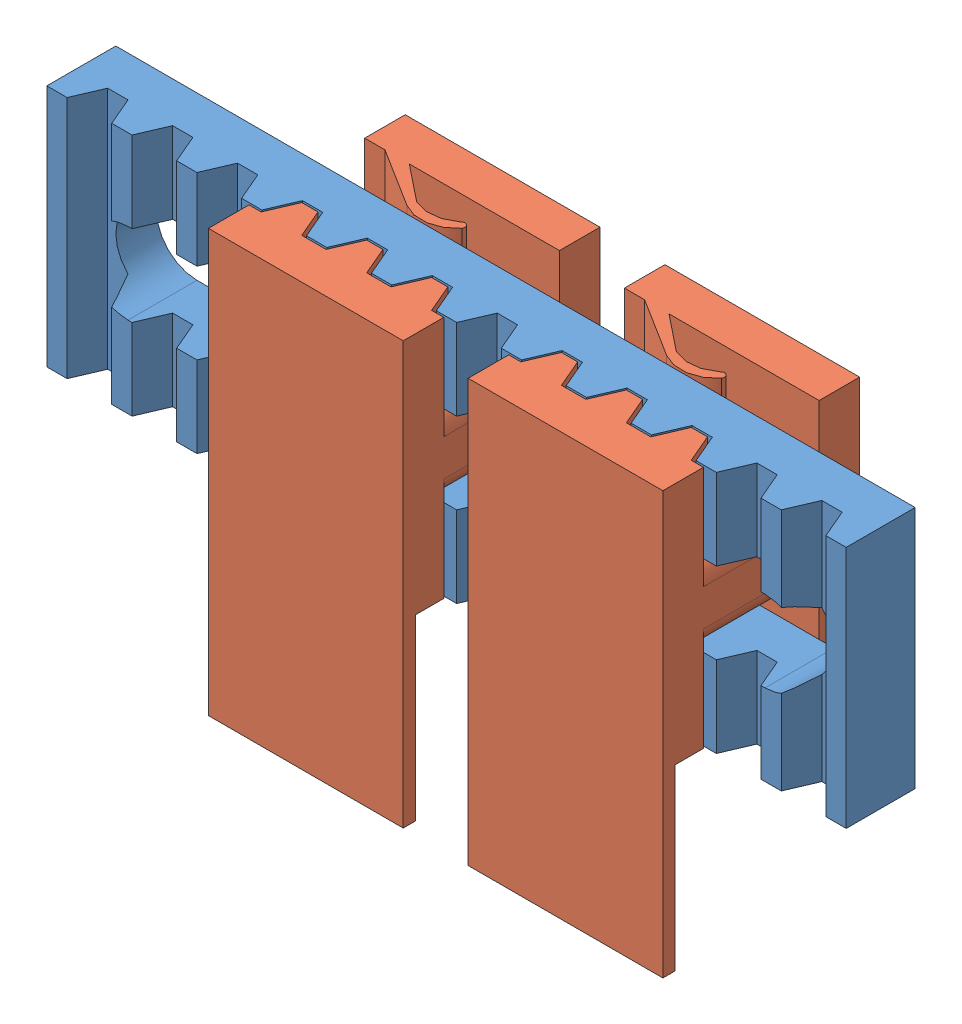
SolidWorks assembly locking mechanism, configuration Default. Lengths in mm.
Overall size (197 104 48.5).
3 component instances, 2 part files, 8 mates.
Components (placement in the parent):
- lock-1: lock [Default] at (99.9471 75.9801 126.6201) size (197 60 17)
- thigh-2: thigh [Default] at (73.7886 135.9801 154.1201) x (-1 0 0) z (0 0 1) size (48 104 48.5)
- thigh-3: thigh [Default] at (137.7886 135.9801 154.1201) x (-1 0 0) z (0 0 1) size (48 104 48.5)
Mates (geometry in assembly coordinates):
- Coincident1: coincident aligned: plane of lock-1 through (99.9471 135.9801 126.6201) normal (0 1 0); plane of thigh-2 through (73.7886 135.9801 154.1201) normal (0 1 0)
- Parallel1: parallel aligned: plane of lock-1 through (99.9471 135.9801 126.6201) normal (0 0 -1); plane of thigh-2 through (73.7886 135.9801 105.6201) normal (0 0 -1)
- Coincident4: coincident aligned: plane of lock-1 through (99.9471 135.9801 126.6201) normal (0 1 0); plane of thigh-3 through (137.7886 135.9801 154.1201) normal (0 1 0)
- Parallel2: parallel aligned: plane of lock-1 through (99.9471 135.9801 126.6201) normal (0 0 -1); plane of thigh-3 through (137.7886 135.9801 105.6201) normal (0 0 -1)
- Distance9: distance = 0.5 mm anti-aligned: plane of thigh-2 through (93.7768 75.9801 137.1201) normal (0 0 -1); plane of lock-1 through (99.9471 135.9801 136.6201) normal (0 0 1)
- Distance10: distance = 0.5 mm anti-aligned: plane of lock-1 through (99.9471 135.9801 136.6201) normal (0 0 1); plane of thigh-3 through (141.7768 75.9801 137.1201) normal (0 0 -1)
- Distance11: distance = 0.5 mm anti-aligned: plane of thigh-2 through (57.7768 75.9801 137.1201) normal (-0.919145 0 -0.393919); plane of lock-1 through (67.6626 135.9801 112.7839) normal (0.919145 0 0.393919)
- Distance12: distance = 0.5 mm anti-aligned: plane of thigh-3 through (121.7768 75.9801 137.1201) normal (-0.919145 0 -0.393919); plane of lock-1 through (121.7316 135.9801 135.9563) normal (0.919145 0 0.393919)
